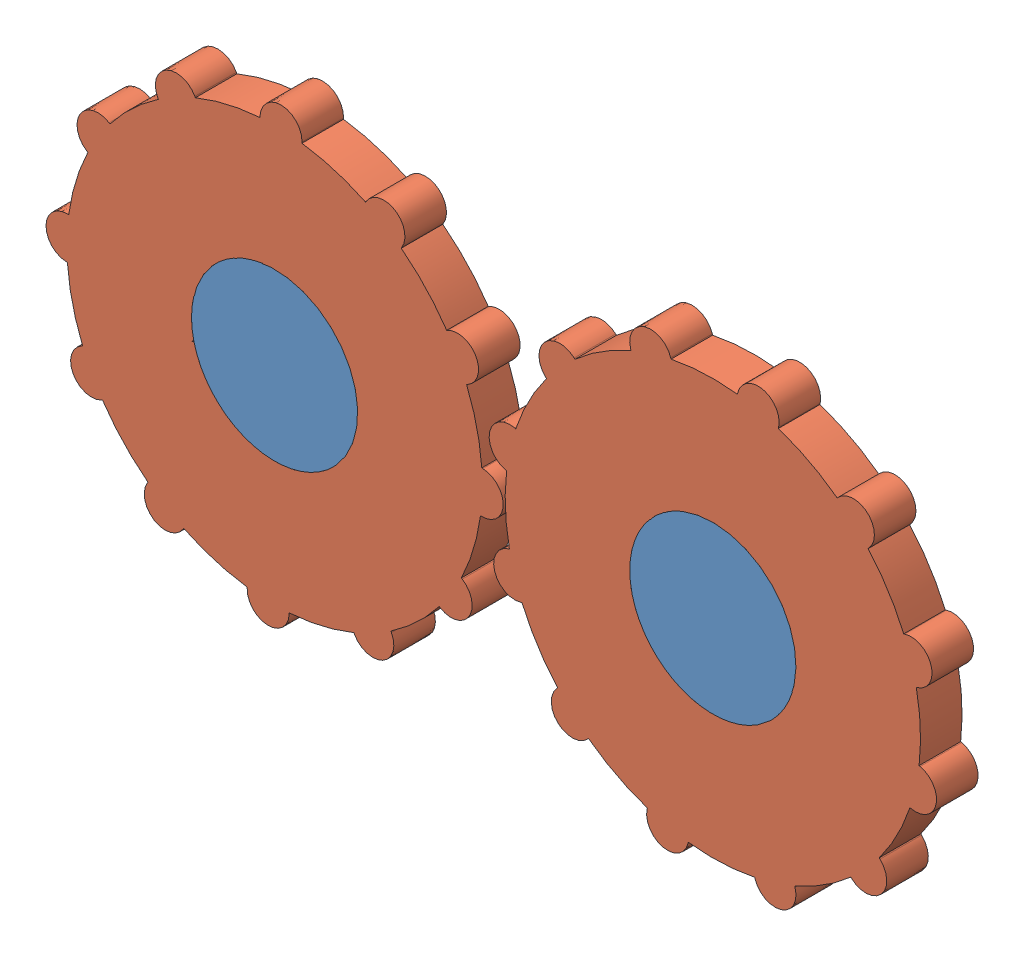
SolidWorks assembly Assem3, configuration Default. Lengths in mm.
Overall size (231.23 138.01 10).
3 component instances, 2 part files, 4 mates.
Components (placement in the parent):
- plane_3d_3-1: plane_3d_3 [Default] at (41.2696 82.5704 114.0541) size (145.5 40 10)
- gear_3d-1: gear_3d [Default] at (-10.0994 77.5395 114.0541) x (0.999524 -0.030837 0) z (0 0 1) size (110.11 110.11 10)
- gear_3d-2: gear_3d [Default] at (95.4006 77.5395 114.0541) x (0.954181 0.299231 0) z (0 0 1) size (110.11 110.11 10)
Mates (geometry in assembly coordinates):
- Coincident1: coincident aligned: plane of plane_3d_3-1 through (41.2696 82.5704 124.0541) normal (0 0 1); plane of gear_3d-1 through (-10.0994 77.5395 124.0541) normal (0 0 1)
- Coincident2: coincident aligned: plane of plane_3d_3-1 through (41.2696 82.5704 124.0541) normal (0 0 1); plane of gear_3d-2 through (95.4006 77.5395 124.0541) normal (0 0 1)
- Coincident3: coincident aligned: circle of plane_3d_3-1; circle of gear_3d-1
- Coincident4: coincident aligned: circle of plane_3d_3-1; circle of gear_3d-2
